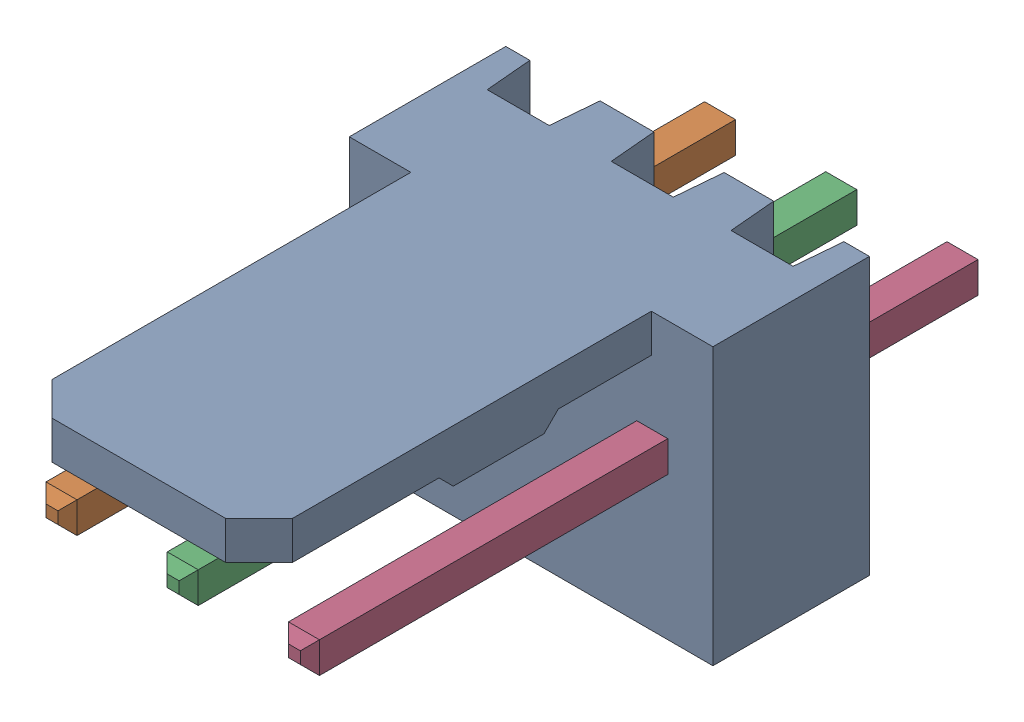
SolidWorks assembly Molex PCB 3 pin v2 v6_2, configuration Predeterminado. Lengths in mm.
Overall size (7.62 5.79 14.92).
4 component instances, 2 part files, 0 mates.
Components (placement in the parent):
- BASE9710016_2-1: BASE9710016_2 [Predeterminado] at (2.54 2.895 -8.22) size (7.62 5.79 11.5)
- PINO9710016_2-1: PINO9710016_2 [Predeterminado] at (1.27 3.325 -0.72) size (0.65 0.65 14.2)
- PINO9710016_2-2: PINO9710016_2 [Predeterminado] at (3.81 3.325 -0.72) size (0.65 0.65 14.2)
- PINO9710016_2-3: PINO9710016_2 [Predeterminado] at (6.35 3.325 -0.72) size (0.65 0.65 14.2)
